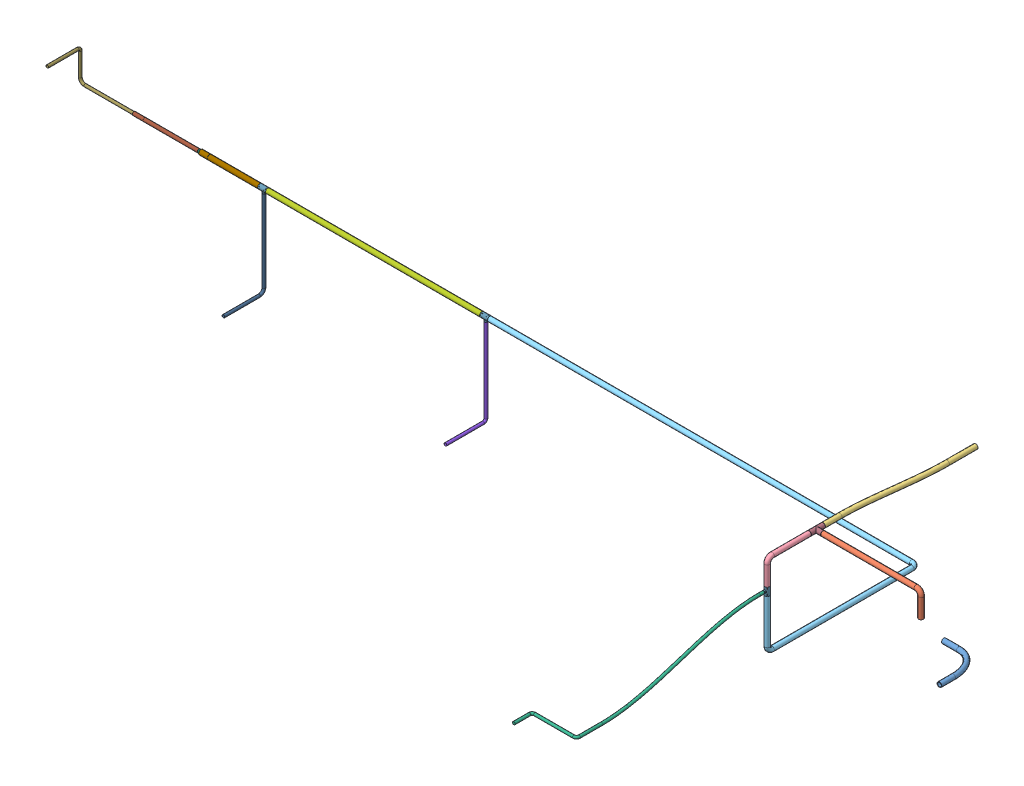
SolidWorks assembly Tube_1-20-ASSEM, configuration Default. Lengths in mm.
Overall size (4734.39 843.48 2699.64).
18 component instances, 15 part files, 0 mates.
Components (placement in the parent):
- Tube-875X095^Tube_1-20-ASSEM-1: Tube-875X095^Tube_1-20-ASSEM [Tube .875in OD X .095in Wall] at (2023.3698 915.4458 -250.9207) x (0.707107 0.707107 0) z (0 0 -1) size (166.61 139.66 221.06) (virtual)
- Tube-875X095_32^Tube_1-20-ASSEM-1: Tube-875X095_32^Tube_1-20-ASSEM [Tube .875in OD X .095in Wall] at (1728.0948 934.3467 -460.0567) x (0.707107 0 0.707107) z (0 1 0) size (343.93 343.93 123.97) (virtual)
- Tube-875X095_33^Tube_1-20-ASSEM-1: Tube-875X095_33^Tube_1-20-ASSEM [Tube .875in OD X .095in Wall] at (1269.6164 1044.6138 -1174.4067) x (0.707107 0.707107 0) z (0 0 1) size (44.73 48.4 681.01) (virtual)
- Tube-875X095_34^Tube_1-20-ASSEM-1: Tube-875X095_34^Tube_1-20-ASSEM [Tube .875in OD X .095in Wall] at (1235.1889 1047.2083 -426.7192) x (0.707107 0.707107 0) z (0 0 1) size (105.74 105.74 206.38) (virtual)
- Tube-875X095_35^Tube_1-20-ASSEM-1: Tube-875X095_35^Tube_1-20-ASSEM [Tube .875in OD X .095in Wall] at (1235.1889 906.3958 -231.4567) x (0.707107 0 0.707107) z (0 -1 0) size (1935.85 1431.56 251.3) (virtual)
- Tube-500X065_9^Tube_1-20-ASSEM-1: Tube-500X065_9^Tube_1-20-ASSEM [Tube .500in OD X .065in Wall] at (1235.1889 915.4458 -222.4067) x (0.707107 0.707107 0) z (0 0 1) size (260.05 159.75 978.24) (virtual)
- Tube-875X095_36^Tube_1-20-ASSEM-1: Tube-875X095_36^Tube_1-20-ASSEM [Tube .875in OD X .095in Wall] at (-793.7023 666.2083 -931.5442) x (0 0.707107 0.707107) z (-1 0 0) size (22.23 22.23 1023.3) (virtual)
- Tube-500X065_10^Tube_1-20-ASSEM-1: Tube-500X065_10^Tube_1-20-ASSEM [Tube .500in OD X .065in Wall] at (-784.6523 657.1583 -931.5442) x (0.707107 0 0.707107) z (0 -1 0) size (145.08 145.08 421.8) (virtual)
- Tube-875X095_37^Tube_1-20-ASSEM-1: Tube-875X095_37^Tube_1-20-ASSEM [Tube .875in OD X .095in Wall] at (-1835.1023 666.2083 -931.5442) x (0 0.707107 0.707107) z (-1 0 0) size (22.23 22.23 285.75) (virtual)
- Tube-500X065_11^Tube_1-20-ASSEM-1: Tube-500X065_11^Tube_1-20-ASSEM [Tube .500in OD X .065in Wall] at (-1826.0523 657.1583 -931.5442) x (0.707107 0 0.707107) z (0 -1 0) size (145.08 145.08 421.8) (virtual)
- Tube-625X065_1^Tube_1-20-ASSEM-1: Tube-625X065_1^Tube_1-20-ASSEM [Tube .625in OD X .065in Wall] at (-2120.8523 666.2083 -931.5442) x (0 0.707107 0.707107) z (-1 0 0) size (15.88 15.88 304.8) (virtual)
- Tube-500X065_12^Tube_1-20-ASSEM-1: Tube-500X065_12^Tube_1-20-ASSEM [Tube .500in OD X .065in Wall] at (-2425.6523 666.2083 -931.5442) x (0 0.707107 0.707107) z (-1 0 0) size (220.27 114.8 268.22) (virtual)
- tee-ss-1: tee-ss [Tee .875in OD X .095in Wall] at (1235.1889 1047.2083 -460.0567) x (0 0 1) z (0 1 0) size (86.67 54.45 22.23)
- Reducing Tee-1: Reducing Tee [0.875IN x 0.5IN Tee] at (1235.1889 915.4458 -231.4567) x (1 0 0) z (0 -1 0) size (22.23 40.16 58.1)
- Reducing Tee-2: Reducing Tee [0.875IN x 0.5IN Tee] at (-784.6523 666.2083 -931.5442) x (0 0 1) z (1 0 0) size (22.23 40.16 58.1)
- Reducing Tee-3: Reducing Tee [0.875IN x 0.5IN Tee] at (-1826.0523 666.2083 -931.5442) x (0 0 1) z (1 0 0) size (22.23 40.16 58.1)
- Reducer-2: Reducer [0.875IN x 0.625IN] at (-2130.8523 666.2083 -931.5442) x (0 1 0) z (1 0 0) size (22.19 22.19 70.8)
- Reducer-3: Reducer [0.625IN x 0.5IN] at (-2435.6523 666.2083 -931.5442) x (0 1 0) z (1 0 0) size (15.86 15.86 70.8)
